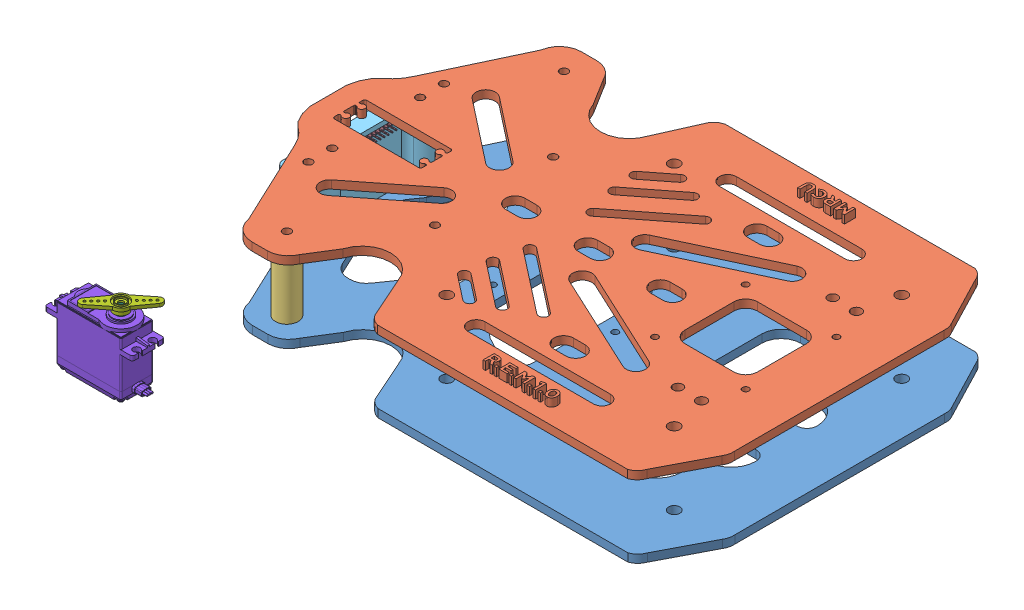
SolidWorks assembly Assem5, configuration Default. Lengths in mm.
Overall size (338.49 81.48 269.85).
11 component instances, 8 part files, 21 mates.
Components (placement in the parent):
- REM_Chassis_Base_Part1-1: REM_Chassis_Base_Part1 [Default] at (-74.8888 3.8703 25.0404) size (316.75 5 215.53)
- REM_Chassis_Upper_Part2-1: REM_Chassis_Upper_Part2 [Default] at (-56.1742 48.8703 25.7921) size (316.75 10 215.53)
- REM_Chassis_Holder_Part4-1: REM_Chassis_Holder_Part4 [Default] at (-111.531 8.8703 -11.5899) size (14 40 14)
- LCD_1602A-1: LCD_1602A [Default] at (-190.5379 10.8524 64.9815) x (-0.001296 0 -0.999999) z (0 1 0) size (80 15.1 36.22)
- REM_Chassis_Holder_Part4-2: REM_Chassis_Holder_Part4 [Default] at (-154.1211 8.8703 110.9058) size (14 40 14)
- REM_Chassis_Holder_Part4-3: REM_Chassis_Holder_Part4 [Default] at (-154.1211 8.8703 -60.8251) size (14 40 14)
- REM_Chassis_Holder_Part4-4: REM_Chassis_Holder_Part4 [Default] at (-111.531 8.8703 61.6706) size (14 40 14)
- REM_LCD_Holder_Part3-4: REM_LCD_Holder_Part3 [Default] at (-184.5896 8.8703 25.0462) x (0.001296 0 0.999999) z (-0.999999 0 0.001296) size (99.2 40 21.59)
- Engrane servomotr-1: Engrane servomotr [Défaut] at (-198.4595 -22.5088 169.3886) size (6 10 6)
- MG995_Gear2-1: MG995_Gear2 [Défaut] at (-198.4595 23.6912 169.3886) x (0.725126 0 0.688616) z (0 -1 0) size (11.5 38 5)
- Servomotor 1-2: Servomotor 1 [Défaut] at (-208.5595 4.4912 169.3886) size (55.35 39.9 20.1)
Mates (geometry in assembly coordinates):
- Coincident2: coincident anti-aligned: plane of REM_Chassis_Base_Part1-1 through (-221.9061 8.8703 -22.3474) normal (0 1 0); plane of REM_Chassis_Holder_Part4-1 through (-111.531 8.8703 -11.5899) normal (0 -1 0)
- Coincident3: coincident anti-aligned: plane of REM_Chassis_Base_Part1-1 through (-221.9061 8.8703 -22.3474) normal (0 1 0); plane of REM_Chassis_Holder_Part4-2 through (-154.1211 8.8703 110.9058) normal (0 -1 0)
- Coincident8: coincident anti-aligned: plane of REM_Chassis_Base_Part1-1 through (-221.9061 8.8703 -22.3474) normal (0 1 0); plane of REM_LCD_Holder_Part3-4 through (-183.1461 8.8703 7.708) normal (0 -1 0)
- Concentric17: concentric: cylinder of REM_Chassis_Base_Part1-1 through (-184.6441 8.8703 67.0344) axis (0 -1 0) radius 2.5; cylinder of REM_LCD_Holder_Part3-4 through (-184.5352 48.8703 67.0462) axis (0 -1 0) radius 2.5
- Concentric22: concentric anti-aligned: cylinder of LCD_1602A-1 through (-192.2384 44.6724 -12.6163) axis (0.999999 0 -0.001296) radius 1.5; cylinder of REM_LCD_Holder_Part3-4 through (-177.0527 44.6724 -12.636) axis (-0.999999 0 0.001296) radius 1.5
- Concentric23: concentric anti-aligned: cylinder of LCD_1602A-1 through (-192.141 44.6724 62.5836) axis (0.999999 0 -0.001296) radius 1.5; cylinder of REM_LCD_Holder_Part3-4 through (-176.9552 44.6724 62.5639) axis (-0.999999 0 0.001296) radius 1.5
- Coincident10: coincident anti-aligned: plane of LCD_1602A-1 through (-190.5897 28.9624 24.9816) normal (0.999999 0 -0.001296); plane of REM_LCD_Holder_Part3-4 through (-190.5896 8.8703 25.054) normal (-0.999999 0 0.001296)
- Concentric27: concentric: cylinder of REM_Chassis_Base_Part1-1 through (-184.6441 8.8703 -16.9537) axis (0 -1 0) radius 2.5; cylinder of REM_LCD_Holder_Part3-4 through (-184.6441 48.8703 -16.9537) axis (0 -1 0) radius 2.5
- Concentric28: concentric aligned: cylinder of REM_Chassis_Base_Part1-1 through (-154.1211 8.8703 110.9058) axis (0 -1 0) radius 2.5; cylinder of REM_Chassis_Holder_Part4-2 through (-154.1211 48.8703 110.9058) axis (0 -1 0) radius 2.5
- Concentric29: concentric aligned: cylinder of REM_Chassis_Base_Part1-1 through (-154.1211 8.8703 -60.8251) axis (0 -1 0) radius 2.5; cylinder of REM_Chassis_Holder_Part4-3 through (-154.1211 48.8703 -60.8251) axis (0 -1 0) radius 2.5
- Coincident11: coincident anti-aligned: plane of REM_Chassis_Base_Part1-1 through (-221.9061 8.8703 -22.3474) normal (0 1 0); plane of REM_Chassis_Holder_Part4-3 through (-154.1211 8.8703 -60.8251) normal (0 -1 0)
- Concentric30: concentric aligned: cylinder of REM_Chassis_Base_Part1-1 through (-111.531 8.8703 -11.5899) axis (0 -1 0) radius 2.5; cylinder of REM_Chassis_Holder_Part4-1 through (-111.531 48.8703 -11.5899) axis (0 -1 0) radius 2.5
- Concentric31: concentric aligned: cylinder of REM_Chassis_Base_Part1-1 through (-111.531 8.8703 61.6706) axis (0 -1 0) radius 2.5; cylinder of REM_Chassis_Holder_Part4-4 through (-111.531 48.8703 61.6706) axis (0 -1 0) radius 2.5
- Coincident12: coincident anti-aligned: plane of REM_Chassis_Base_Part1-1 through (-221.9061 8.8703 -22.3474) normal (0 1 0); plane of REM_Chassis_Holder_Part4-4 through (-111.531 8.8703 61.6706) normal (0 -1 0)
- Concentric32: concentric aligned: cylinder of REM_Chassis_Upper_Part2-1 through (-154.1211 53.8703 110.9058) axis (0 -1 0) radius 2.5; cylinder of REM_Chassis_Holder_Part4-2 through (-154.1211 48.8703 110.9058) axis (0 -1 0) radius 2.5
- Coincident13: coincident anti-aligned: plane of REM_Chassis_Upper_Part2-1 through (-221.8964 48.8703 -22.0507) normal (0 -1 0); plane of REM_Chassis_Holder_Part4-2 through (-154.1211 48.8703 110.9058) normal (0 1 0)
- Concentric33: concentric aligned: cylinder of REM_Chassis_Upper_Part2-1 through (-154.1211 53.8703 -60.8251) axis (0 -1 0) radius 2.5; cylinder of REM_Chassis_Holder_Part4-3 through (-154.1211 48.8703 -60.8251) axis (0 -1 0) radius 2.5
- Concentric35: concentric aligned: cylinder of Engrane servomotr-1 through (-198.4595 -22.5088 169.3886) axis (0 -1 0) radius 3; cylinder of Servomotor 1-2 through (-198.4595 4.4912 169.3886) axis (0 -1 0) radius 3
- Coincident17: coincident aligned: plane of Engrane servomotr-1 through (-201.0595 17.2912 169.3886) normal (0 1 0); plane of Servomotor 1-2 through (-198.4595 17.2912 169.3886) normal (0 1 0)
- Coincident18: coincident anti-aligned: plane of Engrane servomotr-1 through (-200.9595 21.6912 169.3886) normal (0 1 0); plane of MG995_Gear2-1 through (-198.4595 21.6912 169.3886) normal (0 -1 0)
- Concentric36: concentric aligned: cylinder of Engrane servomotr-1 through (-198.4595 21.6912 169.3886) axis (0 1 0) radius 1.25; cylinder of MG995_Gear2-1 through (-198.4595 18.6912 169.3886) axis (0 1 0) radius 1.6
